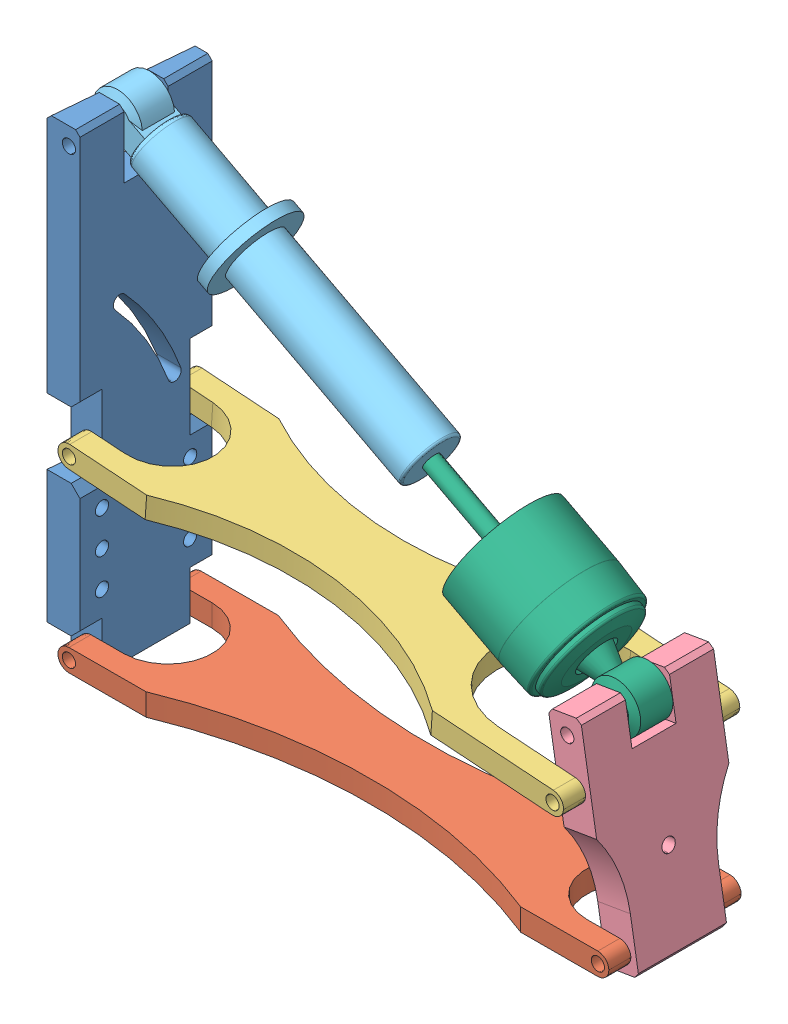
SolidWorks assembly Prototype2, configuration Default. Lengths in mm.
Overall size (340.31 298.37 101.6).
6 component instances, 6 part files, 8 mates.
Components (placement in the parent):
- mounting_plate-1: mounting_plate [Default] at (-76.8906 -84.0916 97.7047) size (19.05 279.4 76.2)
- wishbone-bottom-1: wishbone-bottom [Default] at (-70.5223 -77.7598 110.4047) x (0 0 -1) z (0.999996 0.002865 0) size (76.2 12.7 317.5)
- wishbone-top-3: wishbone-top [Default] at (-70.9718 24.3211 110.4047) x (0 0 -1) z (0.997519 -0.070397 0) size (101.6 12.7 304.8)
- wheel_plate-2: wheel_plate [Default] at (232.8919 -82.1119 97.7047) x (0.986268 0.16515 0) z (0 0 1) size (19.05 127 76.2)
- shock_top-1: shock_top [Default] at (34.0163 131.1029 73.0985) x (0.885801 -0.464064 0) z (-0.464064 -0.885801 0) size (207.96 50.8 50.8)
- shock_bottom-1: shock_bottom [Default] at (136.3104 71.6245 73.0985) x (0.885801 -0.464064 0) z (-0.464064 -0.885801 0) size (176.21 63.5 63.5)
Mates (geometry in assembly coordinates):
- Coincident2: coincident aligned: circle of mounting_plate-1; circle of wishbone-bottom-1
- Coincident3: coincident aligned: circle of mounting_plate-1; circle of wishbone-top-3
- Coincident4: coincident aligned: circle of wishbone-top-3; circle of wheel_plate-2
- Coincident5: coincident anti-aligned: circle of wishbone-bottom-1; circle of wheel_plate-2
- Concentric1: concentric aligned: circle of mounting_plate-1; circle of shock_top-1
- Distance1: distance = 0.7937 mm anti-aligned: plane of shock_top-1 through (-64.1906 185.1484 84.211) normal (0 0 1); plane of mounting_plate-1 through (-76.8906 195.3084 85.0047) normal (0 0 -1)
- Coincident7: coincident aligned: circle of shock_top-1; cylinder of shock_bottom-1 through (79.5566 109.8404 73.0985) axis (-0.885801 0.464064 0) radius 4.7625
- Concentric2: concentric aligned: circle of wheel_plate-2; circle of shock_bottom-1
